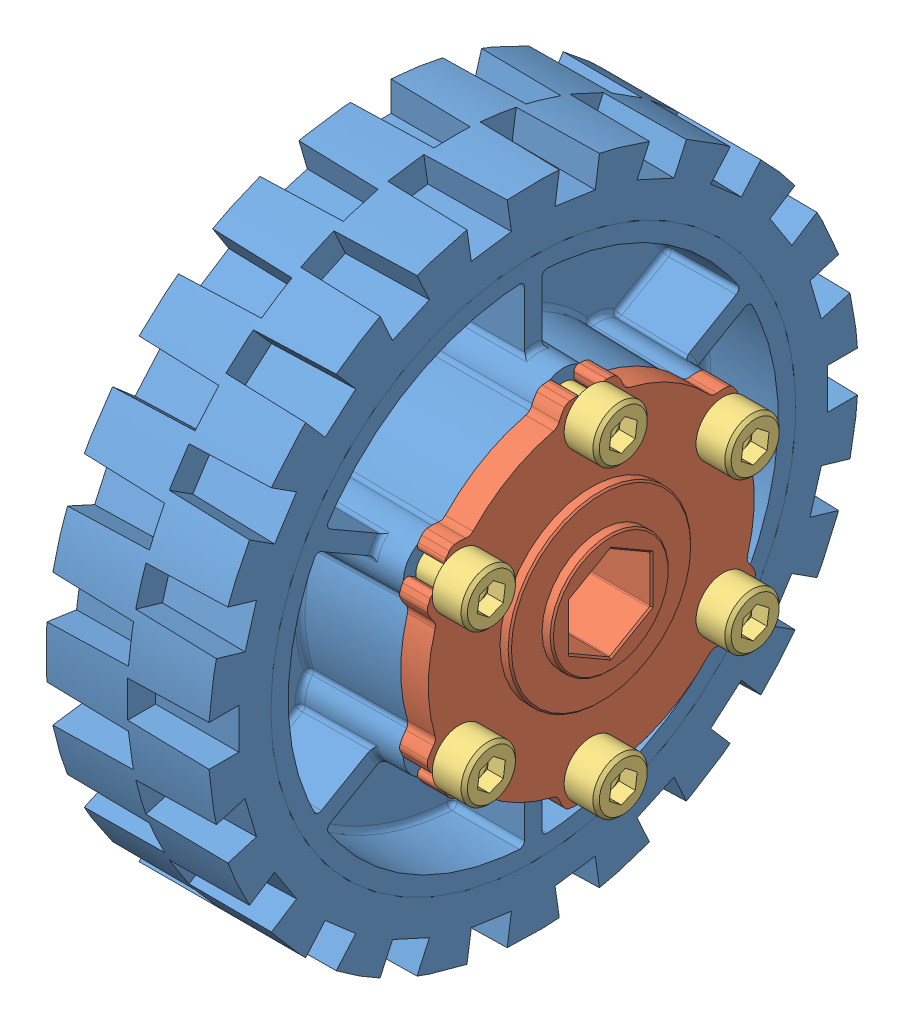
SolidWorks assembly Hex Hub and 4 in HiGrip Wheel, configuration Default. Lengths in mm.
Overall size (44.34 101.6 101.6).
8 component instances, 3 part files, 18 mates.
Components (placement in the parent):
- 4 in HiGrip Wheel-1: 4 in HiGrip Wheel [Default] at (8.0517 0 0) size (35.12 101.6 101.6)
- Hex Hub-1: Hex Hub [Default] at (24.8285 2.5236 2.5343) x (0 1 0) z (0 0 1) size (55.37 25.4 51.33)
- B18.3.1M - 5 x 0.8 x 8 Hex SHCS -- 8NHX-3: B18.3.1M - 5 x 0.8 x 8 Hex SHCS -- 8NHX [B18.3.1M - 5 x 0.8 x 8 Hex SHCS -- 8NHX] at (26.7805 -9.3827 -18.0879) x (-1 0 0) z (0 0.924225 0.381849) size (13 8.5 8.5)
- B18.3.1M - 5 x 0.8 x 8 Hex SHCS -- 8NHX-4: B18.3.1M - 5 x 0.8 x 8 Hex SHCS -- 8NHX [B18.3.1M - 5 x 0.8 x 8 Hex SHCS -- 8NHX] at (26.7805 -21.2889 2.5343) x (-1 0 0) z (0 0.924225 0.381849) size (13 8.5 8.5)
- B18.3.1M - 5 x 0.8 x 8 Hex SHCS -- 8NHX-5: B18.3.1M - 5 x 0.8 x 8 Hex SHCS -- 8NHX [B18.3.1M - 5 x 0.8 x 8 Hex SHCS -- 8NHX] at (26.7805 -9.3827 23.1565) x (-1 0 0) z (0 0.924225 0.381849) size (13 8.5 8.5)
- B18.3.1M - 5 x 0.8 x 8 Hex SHCS -- 8NHX-6: B18.3.1M - 5 x 0.8 x 8 Hex SHCS -- 8NHX [B18.3.1M - 5 x 0.8 x 8 Hex SHCS -- 8NHX] at (26.7805 14.4298 23.1565) x (-1 0 0) z (0 0.924225 0.381849) size (13 8.5 8.5)
- B18.3.1M - 5 x 0.8 x 8 Hex SHCS -- 8NHX-7: B18.3.1M - 5 x 0.8 x 8 Hex SHCS -- 8NHX [B18.3.1M - 5 x 0.8 x 8 Hex SHCS -- 8NHX] at (26.7805 26.3361 2.5343) x (-1 0 0) z (0 0.924225 0.381849) size (13 8.5 8.5)
- B18.3.1M - 5 x 0.8 x 8 Hex SHCS -- 8NHX-8: B18.3.1M - 5 x 0.8 x 8 Hex SHCS -- 8NHX [B18.3.1M - 5 x 0.8 x 8 Hex SHCS -- 8NHX] at (26.7805 14.4298 -18.0879) x (-1 0 0) z (0 0.924225 0.381849) size (13 8.5 8.5)
Mates (geometry in assembly coordinates):
- Coincident1: coincident aligned: line of 4 in HiGrip Wheel-1 through (-12.7 2.5236 2.5343) axis (1 0 0); line of Hex Hub-1 through (4.5051 2.5236 2.5343) axis (1 0 0)
- Coincident3: coincident anti-aligned: plane of 4 in HiGrip Wheel-1 through (17.4625 2.5236 2.5343) normal (1 0 0); plane of Hex Hub-1 through (17.4625 -35.5764 2.5343) normal (-1 0 0)
- Concentric1: concentric anti-aligned: cylinder of 4 in HiGrip Wheel-1 through (-17.4625 26.3361 2.5343) axis (1 0 0) radius 2.159; cylinder of Hex Hub-1 through (24.8285 26.3361 2.5343) axis (-1 0 0) radius 2.5908
- Coincident4: coincident aligned: plane of 4 in HiGrip Wheel-1 through (8.0517 0 0) normal (0 0 1); plane of assembly through (0 0 0) normal (0 0 1)
- Coincident5: coincident aligned: plane of 4 in HiGrip Wheel-1 through (8.0517 0 0) normal (0 1 0); plane of assembly through (0 0 0) normal (0 1 0)
- Coincident6: coincident aligned: plane of 4 in HiGrip Wheel-1 through (0 30.0843 39.547) normal (1 0 0); plane of assembly through (0 0 0) normal (1 0 0)
- Concentric3: concentric anti-aligned: cylinder of Hex Hub-1 through (24.8285 -9.3827 -18.0879) axis (-1 0 0) radius 2.5908; cylinder of B18.3.1M - 5 x 0.8 x 8 Hex SHCS -- 8NHX-3 through (58.5305 -9.3827 -18.0879) axis (1 0 0) radius 4.25
- Coincident7: coincident anti-aligned: plane of Hex Hub-1 through (21.7805 -35.5764 2.5343) normal (1 0 0); plane of B18.3.1M - 5 x 0.8 x 8 Hex SHCS -- 8NHX-3 through (21.7805 -11.0056 -14.16) normal (-1 0 0)
- Concentric4: concentric anti-aligned: cylinder of Hex Hub-1 through (24.8285 -21.2889 2.5343) axis (-1 0 0) radius 2.5908; cylinder of B18.3.1M - 5 x 0.8 x 8 Hex SHCS -- 8NHX-4 through (58.5305 -21.2889 2.5343) axis (1 0 0) radius 4.25
- Coincident8: coincident anti-aligned: plane of Hex Hub-1 through (21.7805 -35.5764 2.5343) normal (1 0 0); plane of B18.3.1M - 5 x 0.8 x 8 Hex SHCS -- 8NHX-4 through (21.7805 -22.9118 6.4622) normal (-1 0 0)
- Concentric5: concentric anti-aligned: cylinder of Hex Hub-1 through (24.8285 -9.3827 23.1565) axis (-1 0 0) radius 2.5908; cylinder of B18.3.1M - 5 x 0.8 x 8 Hex SHCS -- 8NHX-5 through (58.5305 -9.3827 23.1565) axis (1 0 0) radius 4.25
- Coincident9: coincident anti-aligned: plane of Hex Hub-1 through (21.7805 -35.5764 2.5343) normal (1 0 0); plane of B18.3.1M - 5 x 0.8 x 8 Hex SHCS -- 8NHX-5 through (21.7805 -11.0056 27.0845) normal (-1 0 0)
- Concentric6: concentric anti-aligned: cylinder of Hex Hub-1 through (24.8285 14.4298 23.1565) axis (-1 0 0) radius 2.5908; cylinder of B18.3.1M - 5 x 0.8 x 8 Hex SHCS -- 8NHX-6 through (58.5305 14.4298 23.1565) axis (1 0 0) radius 4.25
- Coincident10: coincident anti-aligned: plane of Hex Hub-1 through (21.7805 -35.5764 2.5343) normal (1 0 0); plane of B18.3.1M - 5 x 0.8 x 8 Hex SHCS -- 8NHX-6 through (21.7805 12.8069 27.0845) normal (-1 0 0)
- Concentric7: concentric anti-aligned: cylinder of Hex Hub-1 through (24.8285 26.3361 2.5343) axis (-1 0 0) radius 2.5908; cylinder of B18.3.1M - 5 x 0.8 x 8 Hex SHCS -- 8NHX-7 through (58.5305 26.3361 2.5343) axis (1 0 0) radius 4.25
- Coincident11: coincident anti-aligned: plane of Hex Hub-1 through (21.7805 -35.5764 2.5343) normal (1 0 0); plane of B18.3.1M - 5 x 0.8 x 8 Hex SHCS -- 8NHX-7 through (21.7805 24.7132 6.4622) normal (-1 0 0)
- Concentric8: concentric anti-aligned: cylinder of Hex Hub-1 through (24.8285 14.4298 -18.0879) axis (-1 0 0) radius 2.5908; cylinder of B18.3.1M - 5 x 0.8 x 8 Hex SHCS -- 8NHX-8 through (58.5305 14.4298 -18.0879) axis (1 0 0) radius 4.25
- Coincident12: coincident anti-aligned: plane of Hex Hub-1 through (21.7805 -35.5764 2.5343) normal (1 0 0); plane of B18.3.1M - 5 x 0.8 x 8 Hex SHCS -- 8NHX-8 through (21.7805 12.8069 -14.16) normal (-1 0 0)
